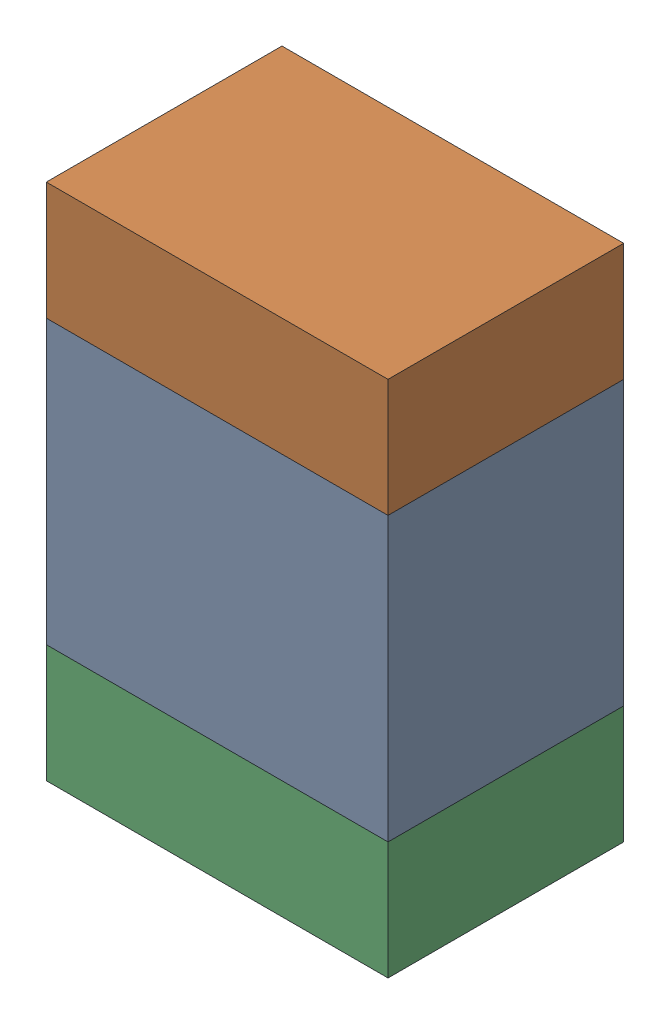
SolidWorks assembly C8-1, configuration Default. Lengths in mm.
Overall size (1.45 2.2 1).
6 component instances, 2 part files, 0 mates.
Components (placement in the parent):
- 959207984-1-1: 959207984-1 [Default] at (115.697 77.2073 0) size (1.45 1.2 1)
  - Extruded-49-1: Extruded-49 [Default] at origin size (1.45 1.2 1)
- 959207848-1-1: 959207848-1 [Default] at (115.697 78.0573 0) size (1.45 0.5 1)
  - Extruded-50-1: Extruded-50 [Default] at origin size (1.45 0.5 1)
- 959207848-1-2: 959207848-1 [Default] at (115.697 76.3573 0) size (1.45 0.5 1)
  - Extruded-50-1: Extruded-50 [Default] at origin size (1.45 0.5 1)
